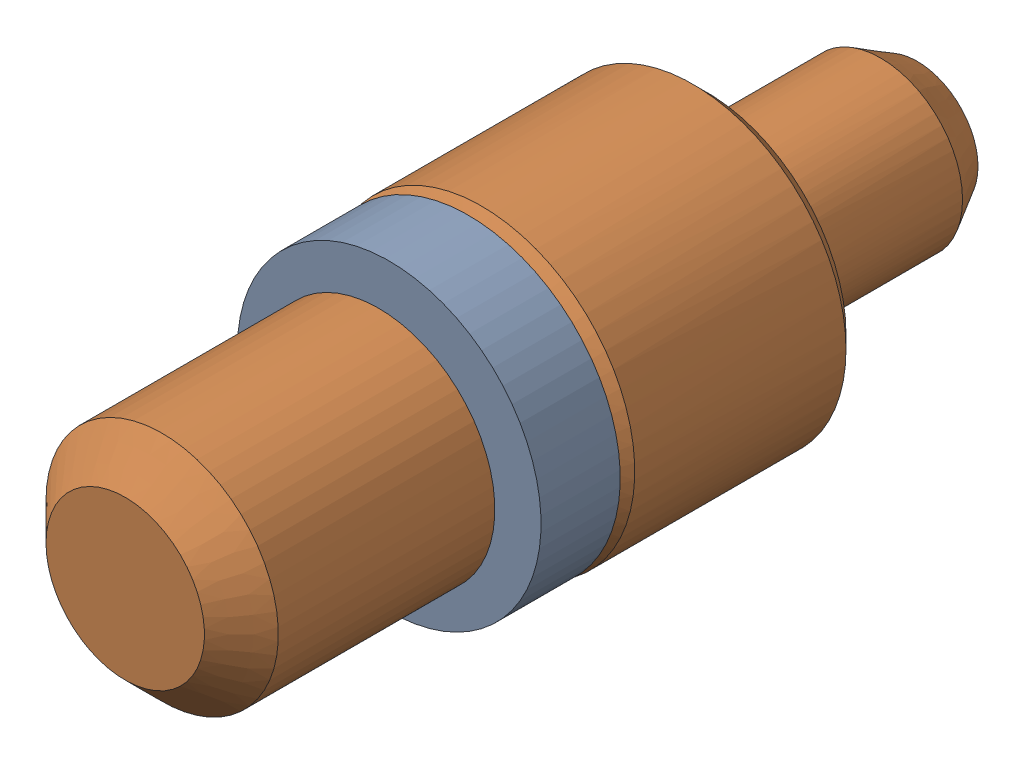
SolidWorks assembly Pogo Pin Asmbly, configuration Default. Lengths in mm.
Overall size (2.95 2.95 7.62).
2 component instances, 2 part files, 0 mates.
Components (placement in the parent):
- Pogo O-Ring-1: Pogo O-Ring [Default] at (73.025 80.137 -6.223) size (2.92 2.92 0.76)
- Pogo Contact Pin-1: Pogo Contact Pin [Default] at (73.025 80.137 -6.223) size (2.95 2.95 7.62)
